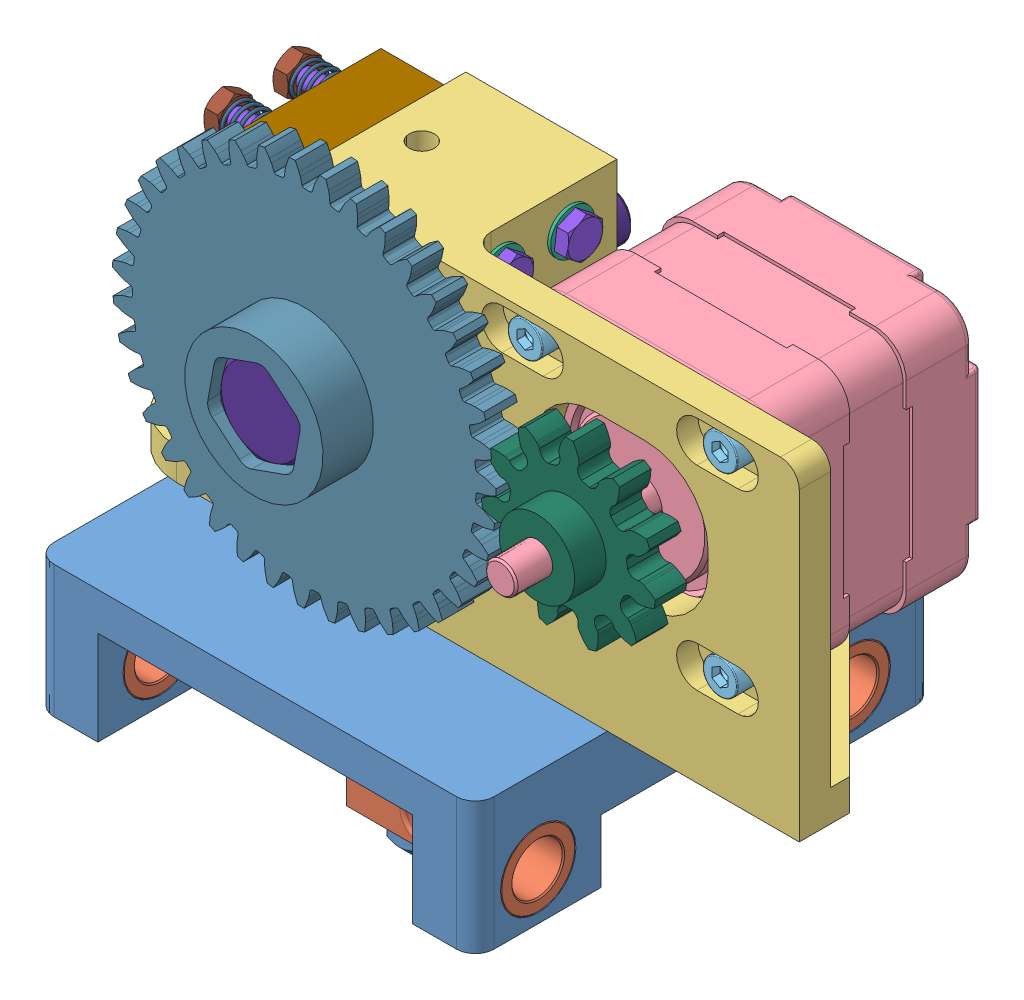
SolidWorks assembly X-Chariot, configuration Défaut. Lengths in mm.
Overall size (113.48 121.48 91.5).
86 component instances, 22 part files, 11 mates.
Components (placement in the parent):
- Chariot_Extrudeuse-1: Chariot_Extrudeuse [Défaut] at (18.2615 62.9748 98.4963) x (1 0 0) z (0 0 -1) size (70 21 91.5)
- BG 12x8x10-4: BG 12x8x10 [Défaut] at (78.2615 49.4748 88.4963) x (0 0.932939 0.360033) z (1 0 0) size (12 12 10)
- X-Tete_Extrusion-2: X-Tete_Extrusion [Défaut] at (67.2193 48.3843 48.66) size (113.48 121.48 59.4)
  - Extruder Body-1: Extruder Body [Défaut] at (51.5422 19.5906 0.8363) x (-1 0 0) z (0 0 -1) size (109 51.5 28)
  - plain washer grade a_din_Washer DIN 125 - A 3.7-1: plain washer grade a_din_Washer DIN 125 - A 3.7 [Défaut] at (-44.9578 19.5906 7.8363) x (0 -1 0) z (0 0 1) size (0.5 8 8) (hidden)
  - plain washer grade a_din_Washer DIN 125 - A 3.7-2: plain washer grade a_din_Washer DIN 125 - A 3.7 [Défaut] at (-44.9578 19.5906 21.8363) x (0 -1 0) z (0 0 1) size (0.5 8 8) (hidden)
  - plain washer grade a_din_Washer DIN 125 - A 3.7-3: plain washer grade a_din_Washer DIN 125 - A 3.7 [Défaut] at (16.0422 19.5906 6.5863) x (0 -1 0) z (0 0 1) size (0.5 8 8) (hidden)
  - plain washer grade a_din_Washer DIN 125 - A 3.7-4: plain washer grade a_din_Washer DIN 125 - A 3.7 [Défaut] at (16.0422 19.5906 18.0863) x (0 -1 0) z (0 0 1) size (0.5 8 8) (hidden)
  - plain washer grade a_din_Washer DIN 125 - A 3.7-5: plain washer grade a_din_Washer DIN 125 - A 3.7 [Défaut] at (16.0422 3.5906 6.5863) x (0 1 0) z (0 0 1) size (0.5 8 8) (hidden)
  - plain washer grade a_din_Washer DIN 125 - A 3.7-6: plain washer grade a_din_Washer DIN 125 - A 3.7 [Défaut] at (16.0422 3.5906 18.0863) x (0 1 0) z (0 0 1) size (0.5 8 8) (hidden)
  - plain washer grade a_din_Washer DIN 125 - A 3.7-7: plain washer grade a_din_Washer DIN 125 - A 3.7 [Défaut] at (-44.9578 3.5906 7.8363) x (0 1 0) z (0 0 1) size (0.5 8 8) (hidden)
  - plain washer grade a_din_Washer DIN 125 - A 3.7-8: plain washer grade a_din_Washer DIN 125 - A 3.7 [Défaut] at (-44.9578 3.5906 21.8363) x (0 1 0) z (0 0 1) size (0.5 8 8) (hidden)
  - hex bolt gradeb_iso_ISO 4015 - M3 x 20 x 20-C-1: hex bolt gradeb_iso_ISO 4015 - M3 x 20 x 20-C [Défaut] at (-44.9578 22.0906 21.8363) x (0 -1 0) z (0 0 1) size (22 6.35 5.5) (hidden)
  - hex bolt gradeb_iso_ISO 4015 - M3 x 20 x 20-C-2: hex bolt gradeb_iso_ISO 4015 - M3 x 20 x 20-C [Défaut] at (-44.9578 22.0906 7.8363) x (0 -1 0) z (0 0 1) size (22 6.35 5.5) (hidden)
  - hex bolt gradeb_iso_ISO 4015 - M3 x 20 x 20-C-3: hex bolt gradeb_iso_ISO 4015 - M3 x 20 x 20-C [Défaut] at (16.0422 22.0906 6.5863) x (0 -1 0) z (0 0 1) size (22 6.35 5.5) (hidden)
  - hex bolt gradeb_iso_ISO 4015 - M3 x 20 x 20-C-4: hex bolt gradeb_iso_ISO 4015 - M3 x 20 x 20-C [Défaut] at (16.0422 22.0906 18.0863) x (0 -1 0) z (0 0 1) size (22 6.35 5.5) (hidden)
  - hex nut style 1 gradeab_iso_Hexagon Nut ISO - 4032 - M3 - D - C-1: hex nut style 1 gradeab_iso_Hexagon Nut ISO - 4032 - M3 - D - C [Défaut] at (-44.9578 0.6906 21.8363) x (1 0 0) z (0 -1 0) size (5.5 6.35 2.4) (hidden)
  - hex nut style 1 gradeab_iso_Hexagon Nut ISO - 4032 - M3 - D - C-2: hex nut style 1 gradeab_iso_Hexagon Nut ISO - 4032 - M3 - D - C [Défaut] at (-44.9578 0.6906 7.8363) x (1 0 0) z (0 -1 0) size (5.5 6.35 2.4) (hidden)
  - hex nut style 1 gradeab_iso_Hexagon Nut ISO - 4032 - M3 - D - C-3: hex nut style 1 gradeab_iso_Hexagon Nut ISO - 4032 - M3 - D - C [Défaut] at (16.0422 0.6906 6.5863) x (1 0 0) z (0 -1 0) size (5.5 6.35 2.4) (hidden)
  - hex nut style 1 gradeab_iso_Hexagon Nut ISO - 4032 - M3 - D - C-4: hex nut style 1 gradeab_iso_Hexagon Nut ISO - 4032 - M3 - D - C [Défaut] at (16.0422 0.6906 18.0863) x (1 0 0) z (0 -1 0) size (5.5 6.35 2.4) (hidden)
  - NEMA 17 Bipolar Stepper Motor-1: NEMA 17 Bipolar Stepper Motor [Défaut] at (23.0422 46.0906 7.3363) x (0 0 1) z (-1 0 0) size (57.01 39.01 39.01)
  - socket head cap screw_iso_ISO 4762 M3 x 5 --- 5C-1: socket head cap screw_iso_ISO 4762 M3 x 5 --- 5C [Défaut] at (7.5422 61.5906 28.4363) x (0 0 -1) z (1 0 0) size (8 5.5 5.5)
  - socket head cap screw_iso_ISO 4762 M3 x 5 --- 5C-2: socket head cap screw_iso_ISO 4762 M3 x 5 --- 5C [Défaut] at (38.5422 61.5906 28.4363) x (0 0 -1) z (1 0 0) size (8 5.5 5.5)
  - socket head cap screw_iso_ISO 4762 M3 x 5 --- 5C-3: socket head cap screw_iso_ISO 4762 M3 x 5 --- 5C [Défaut] at (7.5422 30.5906 28.4363) x (0 0 -1) z (1 0 0) size (8 5.5 5.5)
  - socket head cap screw_iso_ISO 4762 M3 x 5 --- 5C-4: socket head cap screw_iso_ISO 4762 M3 x 5 --- 5C [Défaut] at (38.5422 30.5906 28.4363) x (0 0 -1) z (1 0 0) size (8 5.5 5.5)
  - plain washer grade a_din_Washer DIN 125 - A 3.2-1: plain washer grade a_din_Washer DIN 125 - A 3.2 [Défaut] at (-29.4578 60.0906 8.3363) size (0.5 7 7)
  - plain washer grade a_din_Washer DIN 125 - A 3.2-2: plain washer grade a_din_Washer DIN 125 - A 3.2 [Défaut] at (-29.9578 60.0906 8.3363) size (0.5 7 7)
  - plain washer grade a_din_Washer DIN 125 - A 3.2-3: plain washer grade a_din_Washer DIN 125 - A 3.2 [Défaut] at (-30.4578 60.0906 8.3363) size (0.5 7 7)
  - plain washer grade a_din_Washer DIN 125 - A 3.2-4: plain washer grade a_din_Washer DIN 125 - A 3.2 [Défaut] at (-30.9578 60.0906 8.3363) x (1 0 0) z (0 0.451194 0.892426) size (0.5 7 7)
  - Smooth Rod - f8x23-1: Smooth Rod - f8x23 [Défaut] at (-34.4578 46.0906 2.3363) x (1 0 0) z (0 -1 0) size (8 23 8)
  - plain washer grade a_din_Washer DIN 125 - A 3.2-5: plain washer grade a_din_Washer DIN 125 - A 3.2 [Défaut] at (-5.4578 60.0906 19.3363) x (-1 0 0) z (0 0.924225 0.381849) size (0.5 7 7)
  - plain washer grade a_din_Washer DIN 125 - A 3.2-6: plain washer grade a_din_Washer DIN 125 - A 3.2 [Défaut] at (-5.4578 60.0906 8.3363) x (-1 0 0) z (0 0.924225 0.381849) size (0.5 7 7)
  - plain washer grade a_din_Washer DIN 125 - A 3.2-7: plain washer grade a_din_Washer DIN 125 - A 3.2 [Défaut] at (-5.4578 32.0906 8.3363) x (-1 0 0) z (0 0.924225 0.381849) size (0.5 7 7)
  - plain washer grade a_din_Washer DIN 125 - A 3.2-8: plain washer grade a_din_Washer DIN 125 - A 3.2 [Défaut] at (-5.4578 32.0906 19.3363) x (-1 0 0) z (0 0.924225 0.381849) size (0.5 7 7)
  - plain washer grade a_din_Washer DIN 125 - A 3.2-9: plain washer grade a_din_Washer DIN 125 - A 3.2 [Défaut] at (-29.4578 60.0906 19.3363) size (0.5 7 7)
  - plain washer grade a_din_Washer DIN 125 - A 3.2-10: plain washer grade a_din_Washer DIN 125 - A 3.2 [Défaut] at (-29.4578 32.0906 19.3363) size (0.5 7 7)
  - plain washer grade a_din_Washer DIN 125 - A 3.2-11: plain washer grade a_din_Washer DIN 125 - A 3.2 [Défaut] at (-29.4578 32.0906 8.3363) size (0.5 7 7)
  - plain washer grade a_din_Washer DIN 125 - A 3.2-12: plain washer grade a_din_Washer DIN 125 - A 3.2 [Défaut] at (-29.9578 60.0906 19.3363) size (0.5 7 7)
  - plain washer grade a_din_Washer DIN 125 - A 3.2-13: plain washer grade a_din_Washer DIN 125 - A 3.2 [Défaut] at (-30.4578 60.0906 19.3363) size (0.5 7 7)
  - plain washer grade a_din_Washer DIN 125 - A 3.2-14: plain washer grade a_din_Washer DIN 125 - A 3.2 [Défaut] at (-29.9578 32.0906 19.3363) size (0.5 7 7)
  - plain washer grade a_din_Washer DIN 125 - A 3.2-15: plain washer grade a_din_Washer DIN 125 - A 3.2 [Défaut] at (-30.4578 32.0906 19.3363) size (0.5 7 7)
  - plain washer grade a_din_Washer DIN 125 - A 3.2-16: plain washer grade a_din_Washer DIN 125 - A 3.2 [Défaut] at (-30.9578 32.0906 19.3363) size (0.5 7 7)
  - plain washer grade a_din_Washer DIN 125 - A 3.2-17: plain washer grade a_din_Washer DIN 125 - A 3.2 [Défaut] at (-29.9578 32.0906 8.3363) size (0.5 7 7)
  - plain washer grade a_din_Washer DIN 125 - A 3.2-18: plain washer grade a_din_Washer DIN 125 - A 3.2 [Défaut] at (-30.4578 32.0906 8.3363) size (0.5 7 7)
  - plain washer grade a_din_Washer DIN 125 - A 3.2-19: plain washer grade a_din_Washer DIN 125 - A 3.2 [Défaut] at (-30.9578 32.0906 8.3363) size (0.5 7 7)
  - M3x45_ISO 4015 - M3 x 45 x 12-C-1: M3x45_ISO 4015 - M3 x 45 x 12-C [Défaut] at (-2.9578 60.0906 19.3363) x (-1 0 0) z (0 -0.924225 -0.381849) size (47 6.35 5.5)
  - M3x45_ISO 4015 - M3 x 45 x 12-C-2: M3x45_ISO 4015 - M3 x 45 x 12-C [Défaut] at (-2.9578 32.0906 8.3363) x (-1 0 0) z (0 -0.924225 -0.381849) size (47 6.35 5.5)
  - M3x45_ISO 4015 - M3 x 45 x 12-C-3: M3x45_ISO 4015 - M3 x 45 x 12-C [Défaut] at (-2.9578 32.0906 19.3363) x (-1 0 0) z (0 -0.924225 -0.381849) size (47 6.35 5.5)
  - M3x45_ISO 4015 - M3 x 45 x 12-C-4: M3x45_ISO 4015 - M3 x 45 x 12-C [Défaut] at (-2.9578 60.0906 8.3363) x (-1 0 0) z (0 -0.924225 -0.381849) size (47 6.35 5.5)
  - Idler Body-1: Idler Body [Défaut] at (-41.4578 28.0906 25.3363) x (0 0 -1) z (1 0 0) size (23 36 10)
  - plain washer grade a_din_Washer DIN 125 - A 3.2-20: plain washer grade a_din_Washer DIN 125 - A 3.2 [Défaut] at (-30.9578 60.0906 19.3363) size (0.5 7 7)
  - plain washer grade a_din_Washer DIN 125 - A 3.2-21: plain washer grade a_din_Washer DIN 125 - A 3.2 [Défaut] at (-41.4578 60.0906 8.3363) x (1 0 0) z (0 -0.022823 0.99974) size (0.5 7 7)
  - plain washer grade a_din_Washer DIN 125 - A 3.2-22: plain washer grade a_din_Washer DIN 125 - A 3.2 [Défaut] at (-41.4578 60.0906 19.3363) size (0.5 7 7)
  - plain washer grade a_din_Washer DIN 125 - A 3.2-23: plain washer grade a_din_Washer DIN 125 - A 3.2 [Défaut] at (-41.4578 32.0906 19.3363) size (0.5 7 7)
  - plain washer grade a_din_Washer DIN 125 - A 3.2-24: plain washer grade a_din_Washer DIN 125 - A 3.2 [Défaut] at (-41.4578 32.0906 8.3363) size (0.5 7 7)
  - Ballpoint Pen Spring - Extruder-1: Ballpoint Pen Spring - Extruder [Défaut] at (-42.2078 60.0906 8.3363) x (0 0.991476 -0.130286) z (0 0.130286 0.991476) size (5.53 5.52 5.5)
  - Ballpoint Pen Spring - Extruder-2: Ballpoint Pen Spring - Extruder [Défaut] at (-42.2078 60.0906 19.3363) x (0 0.999694 0.024727) z (0 -0.024727 0.999694) size (5.53 5.52 5.5)
  - Ballpoint Pen Spring - Extruder-3: Ballpoint Pen Spring - Extruder [Défaut] at (-42.2078 32.0906 8.3363) x (0 0.999047 -0.043643) z (0 0.043643 0.999047) size (5.53 5.52 5.5)
  - Ballpoint Pen Spring - Extruder-4: Ballpoint Pen Spring - Extruder [Défaut] at (-42.2078 32.0906 19.3363) x (0 0.978843 -0.20461) z (0 0.20461 0.978843) size (5.53 5.52 5.5)
  - hex nut style 1 gradeab_iso_Hexagon Nut ISO - 4032 - M3 - D - C-5: hex nut style 1 gradeab_iso_Hexagon Nut ISO - 4032 - M3 - D - C [Défaut] at (-47.4578 60.0906 8.3363) x (0 0 -1) z (1 0 0) size (5.5 6.35 2.4)
  - hex nut style 1 gradeab_iso_Hexagon Nut ISO - 4032 - M3 - D - C-6: hex nut style 1 gradeab_iso_Hexagon Nut ISO - 4032 - M3 - D - C [Défaut] at (-47.4578 60.0906 19.3363) x (0 0 -1) z (1 0 0) size (5.5 6.35 2.4)
  - hex nut style 1 gradeab_iso_Hexagon Nut ISO - 4032 - M3 - D - C-7: hex nut style 1 gradeab_iso_Hexagon Nut ISO - 4032 - M3 - D - C [Défaut] at (-46.9578 32.0906 8.3363) x (0 0.019138 -0.999817) z (1 0 0) size (5.5 6.35 2.4)
  - hex nut style 1 gradeab_iso_Hexagon Nut ISO - 4032 - M3 - D - C-8: hex nut style 1 gradeab_iso_Hexagon Nut ISO - 4032 - M3 - D - C [Défaut] at (-47.4578 32.0906 19.3363) x (0 0.048448 -0.998826) z (1 0 0) size (5.5 6.35 2.4)
  - Fourreau-1: Fourreau [Défaut] at (-23.4578 24.5906 13.8363) x (-1 0 0) z (0 0 -1) size (20 44 20)
  - plain washer grade a_din_Washer DIN 125 - A 8.4-1: plain washer grade a_din_Washer DIN 125 - A 8.4 [Défaut] at (-18.9578 46.0906 28.8363) x (0 0 -1) z (0.999888 -0.014961 0) size (1.6 16 16)
  - Large Gear-1: Large Gear [Défaut] at (-47.7391 12.1511 32.0363) x (-0.64677 -0.762685 0) z (0 0 1) size (60.98 60.94 13)
  - plain washer grade a_din_Washer DIN 125 - A 8.4-2: plain washer grade a_din_Washer DIN 125 - A 8.4 [Défaut] at (-18.9578 46.0906 -0.7637) x (0 0 -1) z (0.808623 0.588327 0) size (1.6 16 16)
  - Motor Shaft Pulley - Extruder-1: Motor Shaft Pulley - Extruder [Défaut] at (5.4114 54.4147 32.0363) x (0.336489 -0.941687 0) z (0 0 1) size (27.58 27.61 10)
  - plain washer grade a_din_Washer DIN 125 - A 3.2-25: plain washer grade a_din_Washer DIN 125 - A 3.2 [Défaut] at (-29.4578 19.5906 28.8363) x (0 0 -1) z (1 0 0) size (0.5 7 7)
  - plain washer grade a_din_Washer DIN 125 - A 3.2-26: plain washer grade a_din_Washer DIN 125 - A 3.2 [Défaut] at (-17.4578 19.5906 28.8363) x (0 0 -1) z (1 0 0) size (0.5 7 7)
  - plain washer grade a_din_Washer DIN 125 - A 3.2-27: plain washer grade a_din_Washer DIN 125 - A 3.2 [Défaut] at (-29.4578 19.5906 0.8363) x (0 0 1) z (-1 0 0) size (0.5 7 7)
  - plain washer grade a_din_Washer DIN 125 - A 3.2-28: plain washer grade a_din_Washer DIN 125 - A 3.2 [Défaut] at (-17.4578 19.5906 0.8363) x (0 0 1) z (-1 0 0) size (0.5 7 7)
  - hex bolt gradeb_iso_ISO 4015 - M3 x 20 x 12-C-1: hex bolt gradeb_iso_ISO 4015 - M3 x 20 x 12-C [Défaut] at (-17.4578 19.5906 31.3363) x (0 0 -1) z (1 0 0) size (22 6.35 5.5)
  - hex bolt gradeb_iso_ISO 4015 - M3 x 20 x 12-C-2: hex bolt gradeb_iso_ISO 4015 - M3 x 20 x 12-C [Défaut] at (-29.4578 19.5906 31.3363) x (0 0 -1) z (1 0 0) size (22 6.35 5.5)
  - hex bolt gradeb_iso_ISO 4015 - M3 x 20 x 12-C-3: hex bolt gradeb_iso_ISO 4015 - M3 x 20 x 12-C [Défaut] at (-17.4578 19.5906 -1.6637) x (0 0 1) z (-1 0 0) size (22 6.35 5.5)
  - hex bolt gradeb_iso_ISO 4015 - M3 x 20 x 12-C-4: hex bolt gradeb_iso_ISO 4015 - M3 x 20 x 12-C [Défaut] at (-29.4578 19.5906 -1.6637) x (0 0 1) z (-1 0 0) size (22 6.35 5.5)
  - plain washer grade a_din_Washer DIN 125 - A 8.4-3: plain washer grade a_din_Washer DIN 125 - A 8.4 [Défaut] at (-18.9578 46.0906 30.4363) x (0 0 -1) z (0.820893 -0.571083 0) size (1.6 16 16)
  - hex bolt gradeb_iso_ISO 4015 - M8 x 50 x 22-C-1: hex bolt gradeb_iso_ISO 4015 - M8 x 50 x 22-C [Défaut] at (-18.9578 46.0906 43.7363) x (0 0 -1) z (0.98389 -0.178776 0) size (55.3 15.01 13)
  - radial ball bearing_68_skf_SKF - 608 - Full,DE,AC,Full_68-1: radial ball bearing_68_skf_SKF - 608 - Full,DE,AC,Full_68 [Défaut] at (-18.9578 46.0906 25.3363) x (0 0 1) z (-1 0 0) size (7.01 22 22)
  - radial ball bearing_68_skf_SKF - 608 - Full,DE,AC,Full_68-2: radial ball bearing_68_skf_SKF - 608 - Full,DE,AC,Full_68 [Défaut] at (-18.9578 46.0906 4.3363) x (0 0 1) z (-1 0 0) size (7.01 22 22)
  - radial ball bearing_68_skf_SKF - 608 - Full,DE,AC,Full_68-3: radial ball bearing_68_skf_SKF - 608 - Full,DE,AC,Full_68 [Défaut] at (-34.4578 46.0906 13.8363) x (0 0 -1) z (1 0 0) size (7.01 22 22)
  - Buse-1: Buse [Défaut] at (-23.4578 -32.4094 13.8363) x (0 1 0) z (0 0 1) size (13 8.89 7)
  - Support résistance-1: Support résistance [Défaut] at (-27.4578 -23.4094 5.8363) size (16 8 16)
- BG 12x8x10-8: BG 12x8x10 [Défaut] at (78.2615 49.4748 38.4963) x (0 0.071343 -0.997452) z (1 0 0) size (12 12 10)
- BG 12x8x10-10: BG 12x8x10 [Défaut] at (18.2615 49.4748 88.4963) x (0 0.19777 -0.980248) z (1 0 0) size (12 12 10)
- BG 12x8x10-12: BG 12x8x10 [Défaut] at (18.2615 49.4748 38.4963) x (0 0.28828 -0.957546) z (1 0 0) size (12 12 10)
Mates (geometry in assembly coordinates):
- Coaxiale5: concentric: cylinder of Chariot_Extrudeuse-1 through (88.2615 49.4748 88.4963) axis (-1 0 0) radius 6; cylinder of BG 12x8x10-4 through (88.2615 49.4748 88.4963) axis (-1 0 0) radius 6
- Coïncidente3: coincident: plane of Chariot_Extrudeuse-1 through (88.2615 56.9748 98.4963) normal (1 0 0); plane of BG 12x8x10-4 through (88.2615 49.4748 88.4963) normal (1 0 0)
- Coïncidente4: coincident: plane of Chariot_Extrudeuse-1 through (70.7615 62.9748 14.4963) normal (0 1 0); plane of X-Tete_Extrusion-2/Extruder Body-1 through (118.7615 62.9748 77.4963) normal (0 -1 0)
- Coaxiale6: concentric: cylinder of Chariot_Extrudeuse-1 through (83.2615 51.9748 66.7463) axis (0 -1 0) radius 1.7; cylinder of X-Tete_Extrusion-2/Extruder Body-1 through (83.2615 67.9748 66.7463) axis (0 1 0) radius 1.7
- Parallèle2: parallel: plane of Chariot_Extrudeuse-1 through (18.2615 56.9748 98.4963) normal (0 0 1); plane of X-Tete_Extrusion-2/Extruder Body-1 through (118.7615 114.4748 77.4963) normal (0 0 1)
- Coaxiale10: concentric: cylinder of Chariot_Extrudeuse-1 through (88.2615 49.4748 38.4963) axis (-1 0 0) radius 6; cylinder of BG 12x8x10-8 through (88.2615 49.4748 38.4963) axis (-1 0 0) radius 6
- Coïncidente7: coincident: plane of Chariot_Extrudeuse-1 through (88.2615 56.9748 98.4963) normal (1 0 0); plane of BG 12x8x10-8 through (88.2615 49.4748 38.4963) normal (1 0 0)
- Coaxiale11: concentric: cylinder of Chariot_Extrudeuse-1 through (88.2615 49.4748 88.4963) axis (-1 0 0) radius 6; cylinder of BG 12x8x10-10 through (28.2615 49.4748 88.4963) axis (-1 0 0) radius 6
- Coïncidente8: coincident: plane of Chariot_Extrudeuse-1 through (28.2615 41.9748 98.4963) normal (1 0 0); plane of BG 12x8x10-10 through (28.2615 49.4748 88.4963) normal (1 0 0)
- Coaxiale12: concentric: cylinder of Chariot_Extrudeuse-1 through (88.2615 49.4748 38.4963) axis (-1 0 0) radius 6; cylinder of BG 12x8x10-12 through (28.2615 49.4748 38.4963) axis (-1 0 0) radius 6
- Coïncidente9: coincident: plane of Chariot_Extrudeuse-1 through (28.2615 41.9748 98.4963) normal (1 0 0); plane of BG 12x8x10-12 through (28.2615 49.4748 38.4963) normal (1 0 0)
